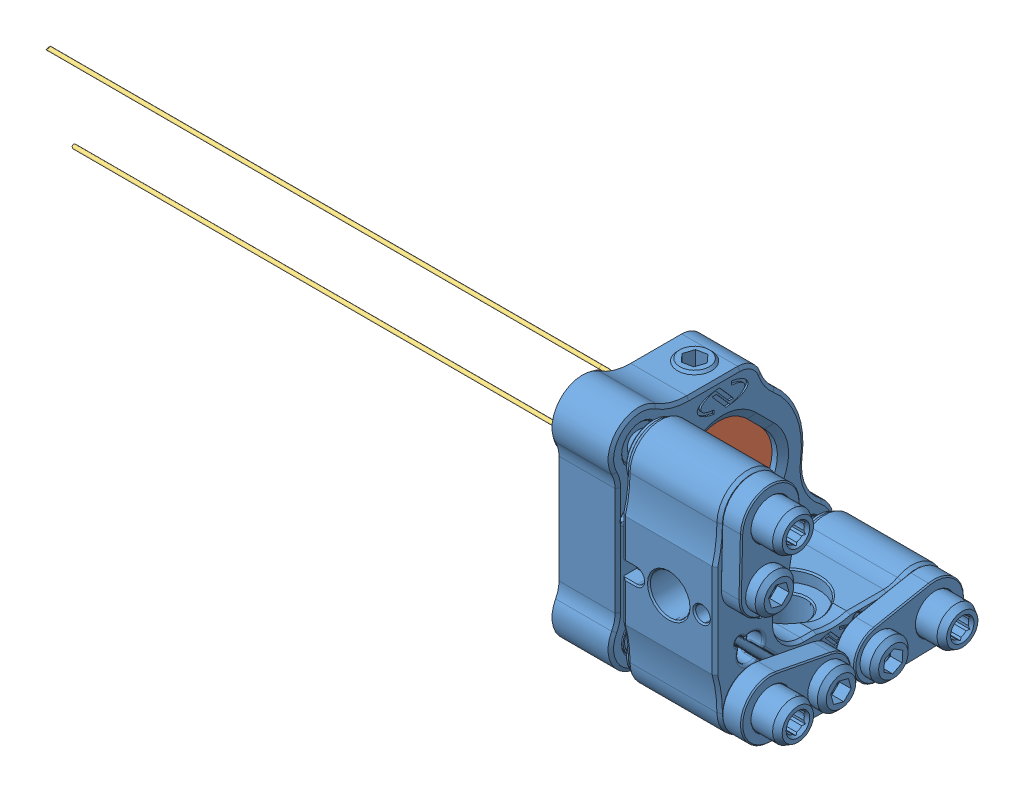
SolidWorks assembly mounted_piezo_mirror, configuration Default. Lengths in mm.
Overall size (89.59 24.89 24.89).
4 component instances, 4 part files, 6 mates.
Components (placement in the parent):
- ST05-F3H_mirror_mount-1: ST05-F3H_mirror_mount [Default] at (15.6025 13.8786 15.9598) x (0 0 -1) z (1 0 0) size (24.89 24.89 23.61)
- piezo_adapter-1: piezo_adapter [Default] at (3.7285 13.8786 15.9598) x (0 0.985412 -0.170186) z (0 -0.170186 -0.985412) size (12.7 4 12.7)
- PK25LA2P2-piezo-1: PK25LA2P2-piezo [Default] at (-3.8016 13.8786 15.9598) x (0 0.259713 -0.965686) z (0 -0.965686 -0.259713) size (8.2 68.55 11.43)
- BB03-E03-Solidworks-1: BB03-E03-Solidworks [Default] at (-5.3017 13.8786 15.9598) x (0 0.942622 0.333863) z (1 0 0) size (7 7 2)
Mates (geometry in assembly coordinates):
- Concentric1: concentric aligned: circle of ST05-F3H_mirror_mount-1; circle of piezo_adapter-1
- Concentric2: concentric aligned: circle of piezo_adapter-1; circle of PK25LA2P2-piezo-1
- Concentric3: concentric aligned: circle of PK25LA2P2-piezo-1; circle of BB03-E03-Solidworks-1
- Coincident2: coincident anti-aligned: plane of PK25LA2P2-piezo-1 through (-25.082 13.8786 15.9598) normal (-1 0 0); plane of BB03-E03-Solidworks-1 through (-25.082 13.8786 15.9598) normal (1 0 0)
- Coincident3: coincident anti-aligned: plane of piezo_adapter-1 through (4.7285 14.5934 20.0985) normal (-1 0 0); plane of PK25LA2P2-piezo-1 through (4.7285 13.8786 15.9598) normal (1 0 0)
- Coincident4: coincident anti-aligned: plane of ST05-F3H_mirror_mount-1 through (7.7285 13.2197 14.3769) normal (-1 0 0); plane of piezo_adapter-1 through (7.7285 13.8786 15.9598) normal (1 0 0)
